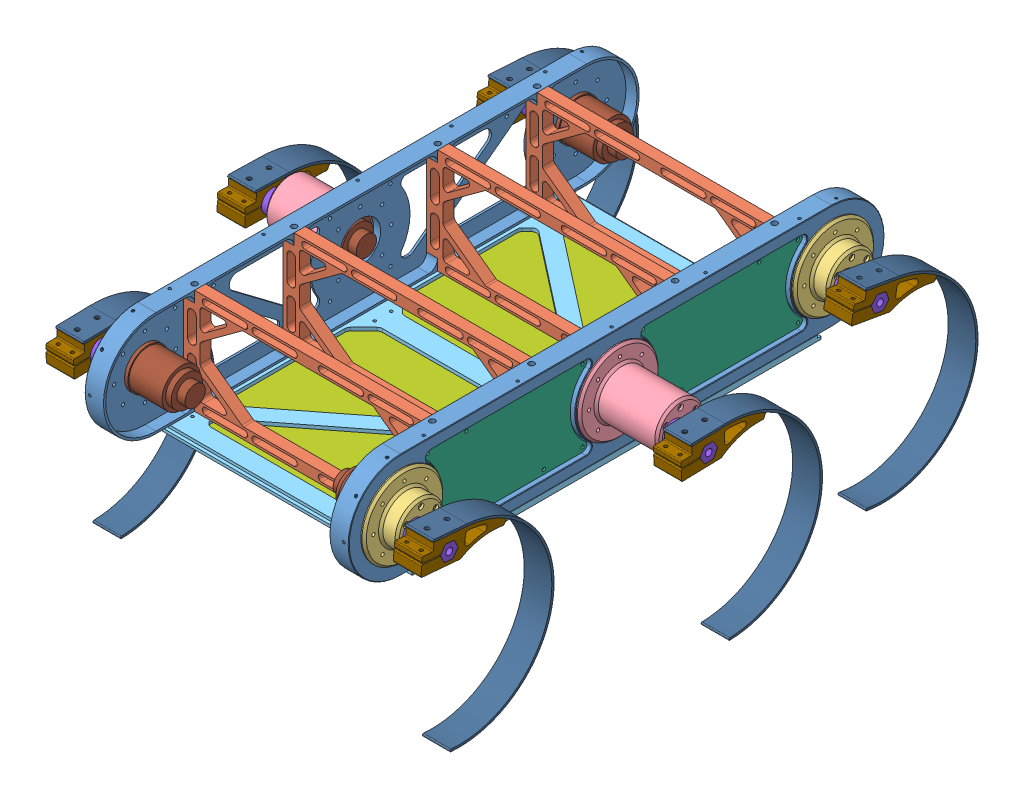
SolidWorks assembly Assembly-round, configuration Default. Lengths in mm.
Overall size (420 219.53 532.71).
50 component instances, 16 part files, 83 mates.
Components (placement in the parent):
- side variant 2-1: side variant 2 [Default] at (-40.1878 15.883 11.2074) size (22.07 95 485)
- cross support-1: cross support [Default] at (-265.1878 -31.617 71.2074) size (225 95 10)
- cross support-2: cross support [Default] at (-265.1878 -31.617 -58.7926) size (225 95 10)
- short-motorholder-1: short-motorholder [Default] at (-21.1878 15.883 -183.7926) x (0 -1 0) z (1 0 0) size (73 73 18)
- gearnotor_w_encoder-1: gearnotor_w_encoder [Default] at (-43.1878 15.883 -183.7926) x (0 -1 0) z (1 0 0) size (36.8 36.8 86.5) (hidden)
- side variant 2-2: side variant 2 [Default] at (-265.1878 15.883 11.2074) x (-1 0 0) z (0 0 -1) size (22.07 95 485)
- cross support-3: cross support [Default] at (-265.1878 -31.617 -148.7926) size (225 95 10)
- cross support-4: cross support [Default] at (-265.1878 -31.617 161.2074) size (225 95 10)
- top new-1: top new [Default] at (-33.1878 63.383 196.2074) size (239 5 370) (hidden)
- long-motorholder-1: long-motorholder [Default] at (18.8122 15.883 11.2074) x (0 -1 0) z (1 0 0) size (73 73 58)
- middlehatch-1: middlehatch [Default] at (-152.6878 68.383 11.2074) x (0 0 -1) z (-1 0 0) size (108 4 207) (hidden)
- sidehatch-1: sidehatch [Default] at (-152.6878 68.383 -103.7926) x (0 0 -1) z (-1 0 0) size (88 4 207) (hidden)
- curved-front-1: curved-front [Default] at (-33.1878 15.883 206.2074) x (-1 0 0) z (0 0 1) size (239 110.02 65.5) (hidden)
- short-motorholder-2: short-motorholder [Default] at (-21.1878 15.883 206.2074) x (0 -1 0) z (1 0 0) size (73 73 18)
- bottom new-1: bottom new [Default] at (-272.1878 -31.617 196.2074) x (-1 0 0) z (0 0 1) size (239 5 370)
- side carb-1: side carb [Default] at (-38.1878 12.1673 187.5666) size (1.5 73 148.23)
- bottom carb-1: bottom carb [Default] at (-152.6878 -36.117 11.2074) x (0 0 -1) z (1 0 0) size (338 1.5 207)
- shaft extension-1: shaft extension [Default] at (-7.6878 15.883 -176.7926) x (0 -0.34296 0.93935) z (-1 0 0) size (20 20 32)
- Part6-1: Part6 [Default] at (-7.6878 -57.5763 -179.2705) x (1 0 0) z (0 0.172663 0.984981) size (25 23 76.39)
- curve prop-1: curve prop [Default] at (-7.6878 -54.8647 -169.5933) x (1 0 0) z (0 0.172663 0.984981) size (25 172 117)
- leg assembly-1: leg assembly [Default] at (250.4069 -62.2369 -124.1919) x (1 0 0) z (0 -0.091273 0.995826) size (103 182.72 128.02) (flexible)
  - curve prop-1: curve prop [Default] at (-218.0947 19.5416 134.3025) x (1 0 0) z (0 0.065545 0.99785) size (25 172 117)
  - Part6-1: Part6 [Default] at (-218.0947 17.8883 124.3895) x (1 0 0) z (0 0.065545 0.99785) size (25 23 76.39)
  - shaft extension-1: shaft extension [Default] at (-218.0947 90.791 134.6747) x (0 0.99785 -0.065545) z (-1 0 0) size (20 20 32)
  - gearnotor_w_encoder-1: gearnotor_w_encoder [Default] at (-253.5947 90.1521 127.7039) x (0 -0.995826 0.091273) z (1 0 0) size (36.8 36.8 86.5)
- leg assembly-2: leg assembly [Default] at (210.4069 -77.6495 80.422) x (1 0 0) z (0 0.020498 0.99979) size (103 182.27 128.02) (flexible)
  - curve prop-1: curve prop [Default] at (-218.0947 19.5416 134.3025) x (1 0 0) z (0 0.065545 0.99785) size (25 172 117)
  - Part6-1: Part6 [Default] at (-218.0947 17.8883 124.3895) x (1 0 0) z (0 0.065545 0.99785) size (25 23 76.39)
  - shaft extension-1: shaft extension [Default] at (-218.0947 90.791 134.6747) x (0 0.99785 -0.065545) z (-1 0 0) size (20 20 32)
  - gearnotor_w_encoder-1: gearnotor_w_encoder [Default] at (-253.5947 90.9345 127.6762) x (0 -0.99979 -0.020498) z (1 0 0) size (36.8 36.8 86.5)
- curve carb-1: curve carb [Default] at (-256.6878 15.883 206.2074) size (208.45 111.69 107.53) (hidden)
- side carb-2: side carb [Default] at (-36.6878 12.1673 -165.1518) x (-1 0 0) z (0 0 -1) size (1.5 73 148.23)
- long-motorholder-2: long-motorholder [Default] at (-324.1878 15.883 11.2074) x (0 1 0) z (-1 0 0) size (73 73 58)
- short-motorholder-4: short-motorholder [Default] at (-284.1878 15.883 -183.7926) x (0 1 0) z (-1 0 0) size (73 73 18)
- short-motorholder-5: short-motorholder [Default] at (-284.1878 15.883 206.2074) x (0 1 0) z (-1 0 0) size (73 73 18)
- leg assembly2-1: leg assembly2 [Default] at (-104.5931 -62.8125 71.1257) x (1 0 0) z (0 -0.086733 0.996232) size (103 182.61 128.02) (flexible)
  - curve prop-1: curve prop [Default] at (-218.0947 19.5416 134.3025) x (1 0 0) z (0 0.065545 0.99785) size (25 172 117)
  - Part6-1: Part6 [Default] at (-218.0947 17.8883 124.3895) x (1 0 0) z (0 0.065545 0.99785) size (25 23 76.39)
  - shaft extension-1: shaft extension [Default] at (-193.0947 90.7221 134.7208) x (0 -0.99785 0.065545) z (1 0 0) size (20 20 32)
  - gearnotor_w_encoder-1: gearnotor_w_encoder [Default] at (-157.5947 90.115 127.7471) x (0 0.996232 -0.086733) z (-1 0 0) size (36.8 36.8 86.5)
- leg assembly2-4: leg assembly2 [Default] at (-144.5931 -69.114 -120.1967) x (1 0 0) z (0 -0.041905 0.999122) size (103 182.15 128.02) (flexible)
  - curve prop-1: curve prop [Default] at (-218.0947 19.5416 134.3025) x (1 0 0) z (0 0.065545 0.99785) size (25 172 117)
  - Part6-1: Part6 [Default] at (-218.0947 17.8883 124.3895) x (1 0 0) z (0 0.065545 0.99785) size (25 23 76.39)
  - shaft extension-1: shaft extension [Default] at (-193.0947 90.7221 134.7208) x (0 -0.99785 0.065545) z (1 0 0) size (20 20 32)
  - gearnotor_w_encoder-1: gearnotor_w_encoder [Default] at (-157.5947 90.4288 127.7269) x (0 0.999122 -0.041905) z (-1 0 0) size (36.8 36.8 86.5)
- leg assembly2-5: leg assembly2 [Default] at (-104.5931 -74.8391 -311.5134) size (103 181.69 128.02) (flexible)
  - curve prop-1: curve prop [Default] at (-218.0947 19.5416 134.3025) x (1 0 0) z (0 0.065545 0.99785) size (25 172 117)
  - Part6-1: Part6 [Default] at (-218.0947 17.8883 124.3895) x (1 0 0) z (0 0.065545 0.99785) size (25 23 76.39)
  - shaft extension-1: shaft extension [Default] at (-193.0947 90.7221 134.7208) x (0 -0.99785 0.065545) z (1 0 0) size (20 20 32)
  - gearnotor_w_encoder-1: gearnotor_w_encoder [Default] at (-157.5947 90.7221 127.7208) x (0 1 0) z (-1 0 0) size (36.8 36.8 86.5)
Mates (geometry in assembly coordinates):
- Coincident1: coincident anti-aligned: plane of side variant 2-1 through (-40.1878 15.883 -183.7926) normal (-1 0 0); plane of cross support-1 through (-40.1878 -31.617 81.2074) normal (1 0 0)
- Concentric1: concentric anti-aligned: circle of side variant 2-1; cylinder of cross support-1 through (-45.1878 53.383 76.2074) axis (0 1 0) radius 1.25
- Coincident3: coincident anti-aligned: circle of side variant 2-1; plane of cross support-1 through (-265.1878 53.383 81.2074) normal (0 1 0)
- Coincident4: coincident anti-aligned: plane of side variant 2-1 through (-50.1878 53.383 -183.7926) normal (0 -1 0); plane of cross support-2 through (-265.1878 53.383 -48.7926) normal (0 1 0)
- Concentric2: concentric aligned: cylinder of side variant 2-1 through (-45.1878 63.383 -53.7926) axis (0 1 0) radius 1.5; cylinder of cross support-2 through (-45.1878 53.383 -53.7926) axis (0 1 0) radius 1.25
- Coincident5: coincident anti-aligned: plane of side variant 2-1 through (-33.1878 15.883 -183.7926) normal (1 0 0); plane of short-motorholder-1 through (-33.1878 15.883 -209.2926) normal (-1 0 0)
- Concentric3: concentric aligned: cylinder of side variant 2-1 through (-33.1878 15.883 -155.7926) axis (1 0 0) radius 1.5; cylinder of short-motorholder-1 through (-30.1878 15.883 -155.7926) axis (1 0 0) radius 1.5
- Concentric4: concentric aligned: cylinder of side variant 2-1 through (-33.1878 15.883 -211.7926) axis (1 0 0) radius 1.5; cylinder of short-motorholder-1 through (-30.1878 15.883 -211.7926) axis (1 0 0) radius 1.5
- Coincident6: coincident anti-aligned: plane of short-motorholder-1 through (-21.1878 15.883 -183.7926) normal (-1 0 0); plane of gearnotor_w_encoder-1 through (-21.1878 15.883 -183.7926) normal (1 0 0)
- Concentric5: concentric anti-aligned: cylinder of short-motorholder-1 through (-15.1878 15.883 -176.7926) axis (1 0 0) radius 6; cylinder of gearnotor_w_encoder-1 through (-14.6878 15.883 -176.7926) axis (-1 0 0) radius 6
- Concentric6: concentric aligned: cylinder of short-motorholder-1 through (-15.1878 31.383 -183.7926) axis (1 0 0) radius 1.5; cylinder of gearnotor_w_encoder-1 through (-26.1878 31.383 -183.7926) axis (1 0 0) radius 1.5
- Coincident7: coincident anti-aligned: plane of cross support-2 through (-255.1878 -31.617 -48.7926) normal (-1 0 0); plane of side variant 2-2 through (-255.1878 15.883 206.2074) normal (1 0 0)
- Coincident8: coincident aligned: plane of cross support-2 through (-265.1878 63.383 -48.7926) normal (0 1 0); plane of side variant 2-2 through (-272.1878 63.383 -183.7926) normal (0 1 0)
- Coincident10: coincident anti-aligned: plane of side variant 2-1 through (-40.1878 15.883 -183.7926) normal (-1 0 0); plane of cross support-2 through (-40.1878 -31.617 -48.7926) normal (1 0 0)
- Concentric7: concentric aligned: cylinder of cross support-2 through (-260.1878 53.383 -53.7926) axis (0 1 0) radius 1.25; cylinder of side variant 2-2 through (-260.1878 63.383 -53.7926) axis (0 1 0) radius 1.5
- Coincident11: coincident anti-aligned: plane of side variant 2-1 through (-50.1878 53.383 -183.7926) normal (0 -1 0); plane of cross support-3 through (-265.1878 53.383 -138.7926) normal (0 1 0)
- Coincident12: coincident anti-aligned: plane of side variant 2-1 through (-40.1878 15.883 -183.7926) normal (-1 0 0); plane of cross support-3 through (-40.1878 -31.617 -138.7926) normal (1 0 0)
- Concentric8: concentric aligned: cylinder of side variant 2-2 through (-260.1878 63.383 -143.7926) axis (0 1 0) radius 1.5; cylinder of cross support-3 through (-260.1878 53.383 -143.7926) axis (0 1 0) radius 1.25
- Coincident13: coincident anti-aligned: plane of side variant 2-2 through (-265.1878 15.883 206.2074) normal (1 0 0); plane of cross support-4 through (-265.1878 -31.617 171.2074) normal (-1 0 0)
- Concentric9: concentric aligned: cylinder of side variant 2-2 through (-260.1878 63.383 166.2074) axis (0 1 0) radius 1.5; cylinder of cross support-4 through (-260.1878 53.383 166.2074) axis (0 1 0) radius 1.25
- Coincident14: coincident anti-aligned: plane of side variant 2-2 through (-255.1878 53.383 206.2074) normal (0 -1 0); plane of cross support-4 through (-265.1878 53.383 171.2074) normal (0 1 0)
- Coincident15: coincident anti-aligned: plane of side variant 2-1 through (-33.1878 63.383 206.2074) normal (0 1 0); plane of top new-1 through (-33.1878 63.383 196.2074) normal (0 -1 0)
- Coincident16: coincident aligned: plane of side variant 2-1 through (-33.1878 15.883 -183.7926) normal (1 0 0); plane of top new-1 through (-33.1878 68.383 196.2074) normal (1 0 0)
- Coincident17: coincident anti-aligned: plane of side variant 2-1 through (-33.1878 15.883 -183.7926) normal (1 0 0); plane of long-motorholder-1 through (-33.1878 15.883 -14.2926) normal (-1 0 0)
- Concentric11: concentric aligned: cylinder of side variant 2-1 through (-33.1878 15.883 39.2074) axis (1 0 0) radius 1.5; cylinder of long-motorholder-1 through (-30.1878 15.883 39.2074) axis (1 0 0) radius 1.5
- Concentric12: concentric aligned: cylinder of side variant 2-1 through (-33.1878 15.883 -16.7926) axis (1 0 0) radius 1.5; cylinder of long-motorholder-1 through (-30.1878 15.883 -16.7926) axis (1 0 0) radius 1.5
- Coincident18: coincident anti-aligned: plane of top new-1 through (-33.1878 66.383 196.2074) normal (0 1 0); plane of middlehatch-1 through (-152.6878 66.383 11.2074) normal (0 -1 0)
- Concentric13: concentric aligned: cylinder of top new-1 through (-53.1878 66.383 61.2074) axis (0 1 0) radius 1.25; cylinder of middlehatch-1 through (-53.1878 68.383 61.2074) axis (0 1 0) radius 1.5
- Concentric14: concentric aligned: cylinder of top new-1 through (-252.1878 66.383 -38.7926) axis (0 1 0) radius 1.25; cylinder of middlehatch-1 through (-252.1878 68.383 -38.7926) axis (0 1 0) radius 1.5
- Coincident20: coincident anti-aligned: plane of top new-1 through (-33.1878 66.383 196.2074) normal (0 1 0); plane of sidehatch-1 through (-152.6878 66.383 -103.7926) normal (0 -1 0)
- Concentric15: concentric aligned: cylinder of top new-1 through (-53.1878 66.383 -63.7926) axis (0 1 0) radius 1.25; cylinder of sidehatch-1 through (-53.1878 68.383 -63.7926) axis (0 1 0) radius 1.5
- Concentric17: concentric aligned: cylinder of top new-1 through (-53.1878 66.383 -143.7926) axis (0 1 0) radius 1.25; cylinder of sidehatch-1 through (-53.1878 68.383 -143.7926) axis (0 1 0) radius 1.5
- Coincident27: coincident aligned: plane of side variant 2-1 through (-33.1878 15.883 -183.7926) normal (1 0 0); plane of curved-front-1 through (-33.1878 15.883 206.2074) normal (1 0 0)
- Concentric19: concentric anti-aligned: cylinder of side variant 2-1 through (-33.1878 15.883 206.2074) axis (-1 0 0) radius 47.5; cylinder of curved-front-1 through (-272.1878 15.883 206.2074) axis (1 0 0) radius 47.5
- Coincident28: coincident anti-aligned: plane of side variant 2-1 through (-33.1878 15.883 -183.7926) normal (1 0 0); plane of short-motorholder-2 through (-33.1878 15.883 180.7074) normal (-1 0 0)
- Concentric20: concentric aligned: cylinder of side variant 2-1 through (-33.1878 15.883 178.2074) axis (1 0 0) radius 1.5; cylinder of short-motorholder-2 through (-30.1878 15.883 178.2074) axis (1 0 0) radius 1.5
- Concentric22: concentric aligned: cylinder of side variant 2-1 through (-33.1878 15.883 234.2074) axis (1 0 0) radius 1.5; cylinder of short-motorholder-2 through (-30.1878 15.883 234.2074) axis (1 0 0) radius 1.5
- Coincident29: coincident anti-aligned: plane of side variant 2-1 through (-33.1878 -31.617 206.2074) normal (0 -1 0); plane of bottom new-1 through (-272.1878 -31.617 196.2074) normal (0 1 0)
- Coincident30: coincident anti-aligned: plane of curved-front-1 through (-272.1878 15.883 196.2074) normal (0 0 -1); plane of bottom new-1 through (-272.1878 -36.617 196.2074) normal (0 0 1)
- Coincident31: coincident aligned: plane of side variant 2-2 through (-272.1878 15.883 206.2074) normal (-1 0 0); plane of bottom new-1 through (-272.1878 -36.617 196.2074) normal (-1 0 0)
- Concentric23: concentric aligned: cylinder of side variant 2-1 through (-38.1878 48.383 38.5935) axis (1 0 0) radius 1.5; cylinder of side carb-1 through (-36.6878 48.383 38.5935) axis (1 0 0) radius 1.5
- Concentric24: concentric aligned: cylinder of side variant 2-1 through (-38.1878 48.383 178.8213) axis (1 0 0) radius 1.5; cylinder of side carb-1 through (-36.6878 48.383 178.8213) axis (1 0 0) radius 1.5
- Coincident33: coincident anti-aligned: plane of side variant 2-1 through (-38.1878 15.883 11.2074) normal (1 0 0); plane of side carb-1 through (-38.1878 12.1673 187.5666) normal (-1 0 0)
- Coincident34: coincident anti-aligned: plane of bottom new-1 through (-272.1878 -34.617 196.2074) normal (0 -1 0); plane of bottom carb-1 through (-152.6878 -34.617 11.2074) normal (0 1 0)
- Concentric25: concentric anti-aligned: cylinder of bottom new-1 through (-53.1878 -34.617 -153.7926) axis (0 -1 0) radius 1.25; cylinder of bottom carb-1 through (-53.1878 -34.617 -153.7926) axis (0 1 0) radius 1.5
- Concentric26: concentric anti-aligned: cylinder of bottom new-1 through (-53.1878 -34.617 176.2074) axis (0 -1 0) radius 1.25; cylinder of bottom carb-1 through (-53.1878 -34.617 176.2074) axis (0 1 0) radius 1.5
- Concentric27: concentric aligned: cylinder of gearnotor_w_encoder-1 through (0.8122 15.883 -176.7926) axis (-1 0 0) radius 3; cylinder of shaft extension-1 through (-7.6878 15.883 -176.7926) axis (-1 0 0) radius 3
- Coincident35: coincident anti-aligned: plane of gearnotor_w_encoder-1 through (-14.6878 15.883 -176.7926) normal (1 0 0); plane of shaft extension-1 through (-14.6878 25.2765 -173.363) normal (-1 0 0)
- Coincident36: coincident anti-aligned: plane of shaft extension-1 through (-7.6878 9.0588 -175.5964) normal (0 -0.984981 0.172663); plane of Part6-1 through (17.3122 9.7352 -171.7381) normal (0 0.984981 -0.172663)
- Coincident37: coincident aligned: plane of shaft extension-1 through (17.3122 18.701 -175.7637) normal (1 0 0); plane of Part6-1 through (17.3122 -57.5763 -179.2705) normal (1 0 0)
- Coincident39: coincident anti-aligned: plane of shaft extension-1 through (-7.6878 20.331 -171.4808) normal (0 0.642021 0.766687); plane of Part6-1 through (17.3122 23.5249 -174.1554) normal (0 -0.642021 -0.766687)
- Concentric28: concentric aligned: cylinder of Part6-1 through (4.8122 27.183 -188.0369) axis (0 0.984981 -0.172663) radius 1.65; cylinder of curve prop-1 through (4.8122 29.153 -188.3823) axis (0 0.984981 -0.172663) radius 2
- Concentric29: concentric aligned: cylinder of Part6-1 through (4.8122 30.291 -170.3073) axis (0 0.984981 -0.172663) radius 1.65; cylinder of curve prop-1 through (4.8122 32.2609 -170.6526) axis (0 0.984981 -0.172663) radius 2
- Coincident42: coincident anti-aligned: plane of Part6-1 through (17.3122 26.147 -193.9468) normal (0 0.984981 -0.172663); plane of curve prop-1 through (17.3122 26.147 -193.9468) normal (0 -0.984981 0.172663)
- Concentric30: concentric anti-aligned: cylinder of long-motorholder-1 through (24.8122 15.883 18.2074) axis (1 0 0) radius 6; cylinder of leg assembly-1/gearnotor_w_encoder-1 through (25.3122 15.883 18.2074) axis (-1 0 0) radius 6
- Coincident43: coincident anti-aligned: plane of long-motorholder-1 through (18.8122 15.883 11.2074) normal (-1 0 0); plane of leg assembly-1/gearnotor_w_encoder-1 through (18.8122 15.883 11.2074) normal (1 0 0)
- Concentric31: concentric aligned: cylinder of long-motorholder-1 through (24.8122 31.383 11.2074) axis (1 0 0) radius 1.5; cylinder of leg assembly-1/gearnotor_w_encoder-1 through (13.8122 31.383 11.2074) axis (1 0 0) radius 1.5
- Coincident44: coincident anti-aligned: plane of short-motorholder-2 through (-21.1878 15.883 206.2074) normal (-1 0 0); plane of leg assembly-2/gearnotor_w_encoder-1 through (-21.1878 15.883 206.2074) normal (1 0 0)
- Concentric32: concentric anti-aligned: cylinder of short-motorholder-2 through (-15.1878 15.883 213.2074) axis (1 0 0) radius 6; cylinder of leg assembly-2/gearnotor_w_encoder-1 through (-14.6878 15.883 213.2074) axis (-1 0 0) radius 6
- Concentric34: concentric aligned: cylinder of short-motorholder-2 through (-15.1878 31.383 206.2074) axis (1 0 0) radius 1.5; cylinder of leg assembly-2/gearnotor_w_encoder-1 through (-26.1878 31.383 206.2074) axis (1 0 0) radius 1.5
- Concentric35: concentric aligned: cylinder of curved-front-1 through (-47.6878 15.883 206.2074) axis (-1 0 0) radius 50.5; cylinder of curve carb-1 through (-48.6878 15.883 206.2074) axis (-1 0 0) radius 50.5
- Concentric37: concentric aligned: cylinder of curved-front-1 through (-252.6878 67.5854 215.3239) axis (0 0.984808 0.173648) radius 1.5; cylinder of curve carb-1 through (-252.6878 67.093 215.2371) axis (0 0.984808 0.173648) radius 1.5
- Concentric38: concentric anti-aligned: cylinder of side variant 2-1 through (-38.1878 48.383 -121.4065) axis (1 0 0) radius 1.5; cylinder of side carb-2 through (-38.1878 48.383 -121.4065) axis (-1 0 0) radius 1.5
- Concentric40: concentric anti-aligned: cylinder of side variant 2-1 through (-38.1878 -16.617 -51.1787) axis (1 0 0) radius 1.5; cylinder of side carb-2 through (-38.1878 -16.617 -51.1787) axis (-1 0 0) radius 1.5
- Coincident45: coincident anti-aligned: plane of side variant 2-1 through (-38.1878 15.883 11.2074) normal (1 0 0); plane of side carb-2 through (-38.1878 12.1673 -165.1518) normal (-1 0 0)
- Coincident46: coincident anti-aligned: plane of side variant 2-2 through (-272.1878 15.883 206.2074) normal (-1 0 0); plane of long-motorholder-2 through (-272.1878 15.883 -14.2926) normal (1 0 0)
- Concentric41: concentric aligned: cylinder of side variant 2-2 through (-272.1878 15.883 39.2074) axis (-1 0 0) radius 1.5; cylinder of long-motorholder-2 through (-275.1878 15.883 39.2074) axis (-1 0 0) radius 1.5
- Concentric42: concentric aligned: cylinder of side variant 2-2 through (-272.1878 15.883 -16.7926) axis (-1 0 0) radius 1.5; cylinder of long-motorholder-2 through (-275.1878 15.883 -16.7926) axis (-1 0 0) radius 1.5
- Coincident47: coincident anti-aligned: plane of side variant 2-2 through (-272.1878 15.883 206.2074) normal (-1 0 0); plane of short-motorholder-4 through (-272.1878 15.883 -209.2926) normal (1 0 0)
- Concentric43: concentric aligned: cylinder of side variant 2-2 through (-272.1878 15.883 -155.7926) axis (-1 0 0) radius 1.5; cylinder of short-motorholder-4 through (-275.1878 15.883 -155.7926) axis (-1 0 0) radius 1.5
- Concentric44: concentric aligned: cylinder of side variant 2-2 through (-272.1878 15.883 -211.7926) axis (-1 0 0) radius 1.5; cylinder of short-motorholder-4 through (-275.1878 15.883 -211.7926) axis (-1 0 0) radius 1.5
- Coincident48: coincident anti-aligned: plane of side variant 2-2 through (-272.1878 15.883 206.2074) normal (-1 0 0); plane of short-motorholder-5 through (-272.1878 15.883 180.7074) normal (1 0 0)
- Concentric45: concentric aligned: cylinder of side variant 2-2 through (-272.1878 15.883 234.2074) axis (-1 0 0) radius 1.5; cylinder of short-motorholder-5 through (-275.1878 15.883 234.2074) axis (-1 0 0) radius 1.5
- Concentric46: concentric aligned: cylinder of side variant 2-2 through (-272.1878 15.883 178.2074) axis (-1 0 0) radius 1.5; cylinder of short-motorholder-5 through (-275.1878 15.883 178.2074) axis (-1 0 0) radius 1.5
- Coincident49: coincident anti-aligned: plane of short-motorholder-5 through (-284.1878 15.883 206.2074) normal (1 0 0); plane of leg assembly2-1/gearnotor_w_encoder-1 through (-284.1878 15.883 206.2074) normal (-1 0 0)
- Concentric47: concentric anti-aligned: cylinder of short-motorholder-5 through (-290.1878 15.883 213.2074) axis (-1 0 0) radius 6; cylinder of leg assembly2-1/gearnotor_w_encoder-1 through (-290.6878 15.883 213.2074) axis (1 0 0) radius 6
- Concentric48: concentric aligned: cylinder of short-motorholder-5 through (-290.1878 23.633 192.784) axis (-1 0 0) radius 1.5; cylinder of leg assembly2-1/gearnotor_w_encoder-1 through (-279.1878 23.633 192.784) axis (-1 0 0) radius 1.5
- Coincident52: coincident anti-aligned: plane of long-motorholder-2 through (-324.1878 15.883 11.2074) normal (1 0 0); plane of leg assembly2-4/gearnotor_w_encoder-1 through (-324.1878 15.883 11.2074) normal (-1 0 0)
- Concentric50: concentric anti-aligned: cylinder of long-motorholder-2 through (-330.1878 15.883 18.2074) axis (-1 0 0) radius 6; cylinder of leg assembly2-4/gearnotor_w_encoder-1 through (-330.6878 15.883 18.2074) axis (1 0 0) radius 6
- Concentric51: concentric aligned: cylinder of long-motorholder-2 through (-330.1878 23.633 -2.216) axis (-1 0 0) radius 1.5; cylinder of leg assembly2-4/gearnotor_w_encoder-1 through (-319.1878 23.633 -2.216) axis (-1 0 0) radius 1.5
- Coincident53: coincident anti-aligned: plane of short-motorholder-4 through (-284.1878 15.883 -183.7926) normal (1 0 0); plane of leg assembly2-5/gearnotor_w_encoder-1 through (-284.1878 15.883 -183.7926) normal (-1 0 0)
- Concentric52: concentric anti-aligned: cylinder of short-motorholder-4 through (-290.1878 15.883 -176.7926) axis (-1 0 0) radius 6; cylinder of leg assembly2-5/gearnotor_w_encoder-1 through (-290.6878 15.883 -176.7926) axis (1 0 0) radius 6
- Concentric53: concentric aligned: cylinder of short-motorholder-4 through (-290.1878 8.133 -197.216) axis (-1 0 0) radius 1.5; cylinder of leg assembly2-5/gearnotor_w_encoder-1 through (-279.1878 8.133 -197.216) axis (-1 0 0) radius 1.5
